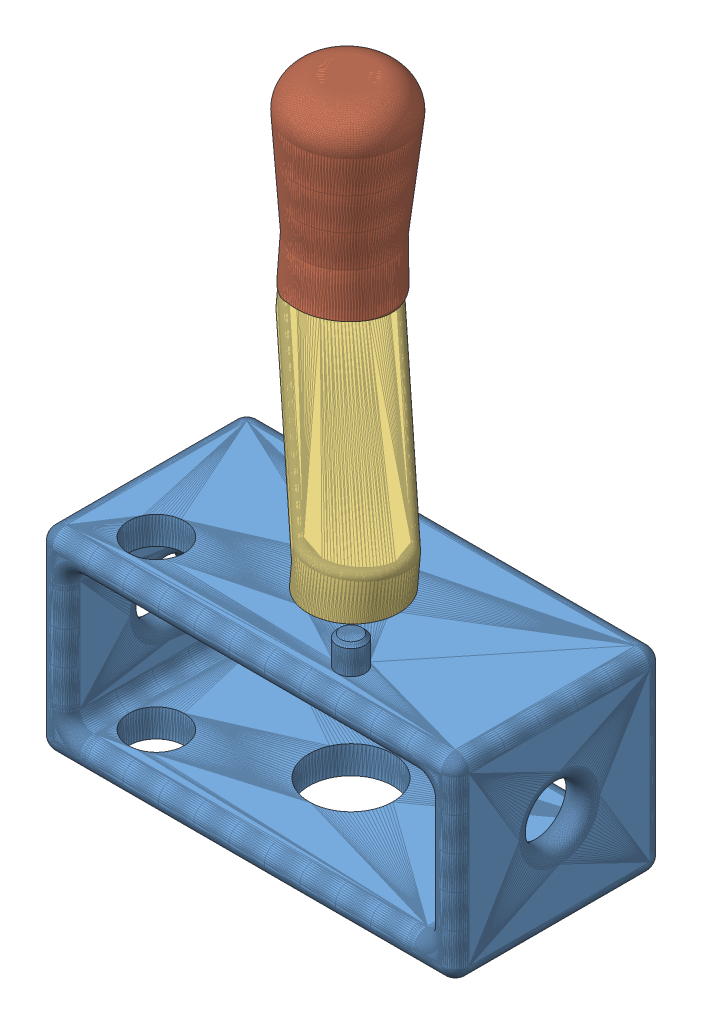
SolidWorks assembly Vital, configuration Default. Lengths in mm.
Overall size (76.83 57.29 60.64).
3 component instances, 3 part files, 6 mates.
Components (placement in the parent):
- Base-1: Base [Default] at (2.6472 31.816 54.7748) size (60 32 30)
- Handle-1: Handle [Default] at (1.0767 19.6725 55.8974) x (-0.713052 0.022751 0.700741) z (-0.700389 0.022223 -0.713415) size (15.68 27.5 15.68)
- Crank-1: Crank [Default] at (3.1231 25.0597 56.9885) x (-0.6863 0.07333 0.723612) z (-0.727313 -0.073092 -0.682403) size (13 17 63)
Mates (geometry in assembly coordinates):
- Coincident6: coincident: point of Handle-1; point of Crank-1
- Distance1: distance = 1.5719 mm: point of Handle-1; point of Crank-1
- Distance3: distance = 0.7896 mm: unknown of Crank-1; moEndPointRef_w of Handle-1
- Parallel3: parallel anti-aligned: line of Base-1 through (-3.3528 45.816 54.7748) axis (0.003634 -0.994564 0.104066); line of Crank-1 through (-0.7519 42.5013 60.4562) axis (-0.003634 0.994564 -0.104066)
- Coincident14: coincident: point of Base-1; point of Crank-1
- Distance6: distance = 1.6127 mm: point of Crank-1; line of Base-1 through (26.6472 41.816 41.7748) axis (-0.955461 0 0.295117)
